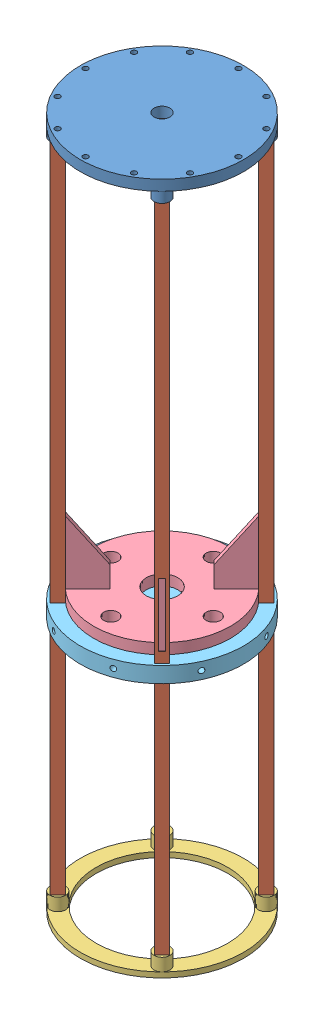
SolidWorks assembly LowerAirframe, configuration Default. Lengths in mm.
Overall size (278.39 834.39 278.39).
8 component instances, 5 part files, 14 mates.
Components (placement in the parent):
- Topring3-1: Topring3 [Default] at (27.5072 118.0983 164.9149) size (196.85 25.4 196.85)
- Stringer-1: Stringer [Default] at (-35.3546 -288.3017 227.7766) x (0 -1 0) z (0.707107 0 0.707107) size (812.8 12.82 12.7)
- Aft_Ring-1: Aft_Ring [Default] at (27.5072 -703.5917 164.9149) x (0 1 0) z (-0.707107 0 -0.707107) size (21.59 196.85 196.85)
- LA-dar_2-1: LA-dar_2 [Default] at (27.5501 -377.2017 164.872) x (-0.707107 0 -0.707107) z (0.707107 0 -0.707107) size (190.5 88.9 190.5)
- Thrustring-2: Thrustring [Default] at (27.4643 -377.2017 164.9578) x (0 0 1) z (1 0 0) size (196.85 19.05 196.85)
- Stringer-5: Stringer [Default] at (-35.3546 -288.3017 102.0531) x (0 -1 0) z (-0.707107 0 0.707107) size (812.8 12.82 12.7)
- Stringer-6: Stringer [Default] at (90.369 -288.3017 102.0531) x (0 -1 0) z (-0.707107 0 -0.707107) size (812.8 12.82 12.7)
- Stringer-7: Stringer [Default] at (90.369 -288.3017 227.7766) x (0 -1 0) z (0.707107 0 -0.707107) size (812.8 12.82 12.7)
Mates (geometry in assembly coordinates):
- Concentric1: concentric anti-aligned: cylinder of Topring3-1 through (-35.3546 120.6383 227.7766) axis (0 -1 0) radius 3.175; cylinder of Stringer-1 through (-35.3546 105.3983 227.7766) axis (0 1 0) radius 3.175
- Coincident1: coincident anti-aligned: plane of Topring3-1 through (-35.3546 105.3983 227.7766) normal (0 -1 0); plane of Stringer-1 through (-35.3546 105.3983 227.7766) normal (0 1 0)
- Coincident3: coincident anti-aligned: plane of Stringer-1 through (-35.3546 -682.0017 227.7766) normal (0 -1 0); plane of Aft_Ring-1 through (-35.3546 -682.0017 227.7766) normal (0 1 0)
- Concentric2: concentric anti-aligned: cylinder of Stringer-1 through (-35.3546 -682.0017 227.7766) axis (0 -1 0) radius 3.175; cylinder of Aft_Ring-1 through (-35.3546 -682.0017 227.7766) axis (0 1 0) radius 3.175
- Concentric3: concentric aligned: circle of Topring3-1; circle of Aft_Ring-1
- Coincident9: coincident aligned: plane of LA-dar_2-1 through (92.657 -364.5017 95.275) normal (0.707107 0 -0.707107); plane of Stringer-6 through (90.4119 -694.7017 93.0299) normal (0.707107 0 -0.707107)
- Coincident10: coincident anti-aligned: plane of LA-dar_2-1 through (25.3051 -377.2017 162.6269) normal (-0.707107 0 -0.707107); plane of Stringer-6 through (92.6577 -288.3017 95.2743) normal (0.707107 0 0.707107)
- Coincident11: coincident anti-aligned: plane of LA-dar_2-1 through (83.6767 -288.3017 104.2552) normal (0 1 0); plane of Stringer-6 through (97.1478 -288.3017 99.7644) normal (0 -1 0)
- Coincident12: coincident anti-aligned: plane of Stringer-1 through (-42.1334 -288.3017 230.0653) normal (0.707107 0 0.707107); plane of LA-dar_2-1 through (25.3051 -377.2017 162.6269) normal (-0.707107 0 -0.707107)
- Parallel2: parallel aligned: plane of LA-dar_2-1 through (29.7952 -377.2017 162.6269) normal (0.707107 0 -0.707107); plane of Stringer-5 through (-35.3975 -694.7017 93.0299) normal (0.707107 0 -0.707107)
- Parallel3: parallel aligned: plane of LA-dar_2-1 through (29.7952 -377.2017 162.6269) normal (0.707107 0 -0.707107); plane of Stringer-7 through (99.3922 -694.7017 227.8195) normal (0.707107 0 -0.707107)
- Coincident13: coincident: plane of Stringer-1 through (-35.3975 -694.7017 236.7998) normal (-0.707107 0 0.707107); plane of Thrustring-2 through (-44.3777 -377.2007 227.8195) normal (0.707107 0 -0.707107)
- Coincident14: coincident: plane of Stringer-1 through (-35.3975 -694.7017 236.7998) normal (0.707107 0 0.707107); plane of Thrustring-2 through (-26.4172 -377.2007 227.8195) normal (-0.707107 0 -0.707107)
- Coincident15: coincident anti-aligned: plane of LA-dar_2-1 through (27.5501 -377.2017 164.872) normal (0 -1 0); plane of Thrustring-2 through (27.4643 -377.2017 164.9578) normal (0 1 0)
